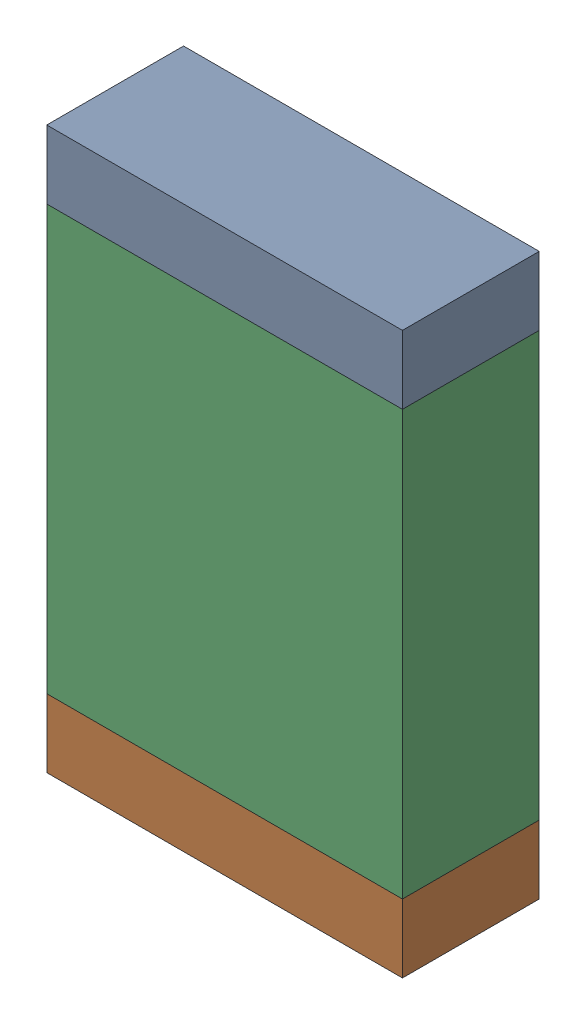
SolidWorks assembly C99, configuration Default. Lengths in mm.
Overall size (1.3 2.05 0.5).
6 component instances, 2 part files, 0 mates.
Components (placement in the parent):
- 836753264-1: 836753264 [Default] at (113.55 71.375 0) size (1.3 0.25 0.5)
  - Extruded_22-1: Extruded_22 [Default] at origin size (1.3 0.25 0.5)
- 836753264-2: 836753264 [Default] at (113.55 69.575 0) size (1.3 0.25 0.5)
  - Extruded_22-1: Extruded_22 [Default] at origin size (1.3 0.25 0.5)
- 836753008-1: 836753008 [Default] at (113.55 70.475 0) size (1.3 1.55 0.5)
  - Extruded_23-1: Extruded_23 [Default] at origin size (1.3 1.55 0.5)
